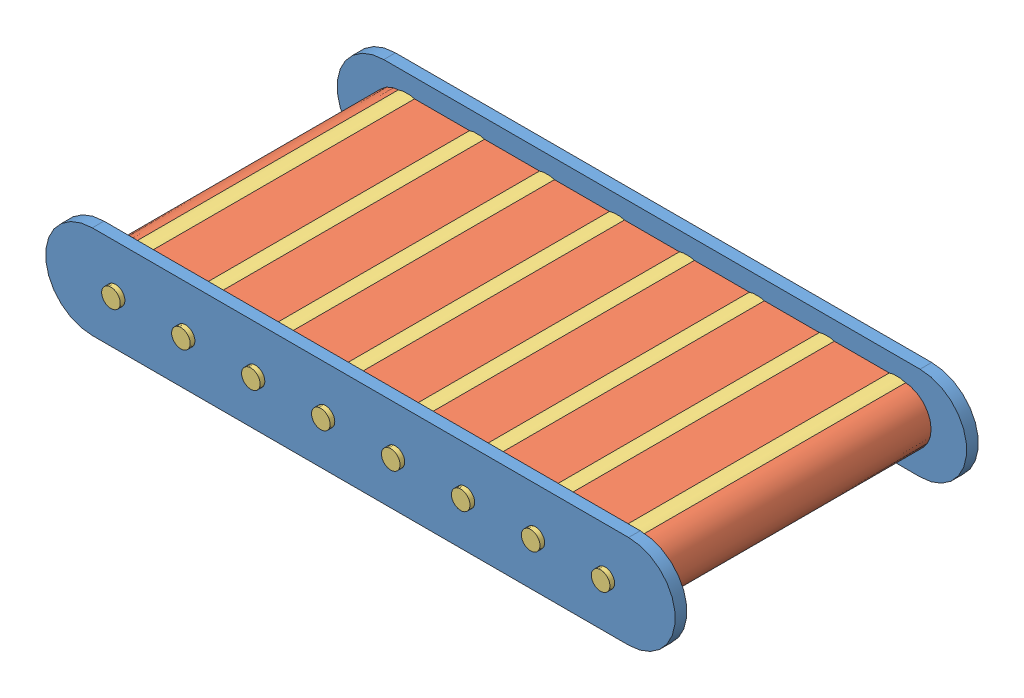
SolidWorks assembly Assem1, configuration Défaut. Lengths in mm.
Overall size (270 40 134).
10 component instances, 3 part files, 4 mates.
Components (placement in the parent):
- ajneb-1: ajneb [Défaut] at (-102.1225 -28.6307 270) size (270 40 130)
- bande-1: bande [Défaut] at (-102.1225 -28.6307 270) size (239.5 24 120)
- rouleau-1: rouleau [Défaut] at (-102.1225 -28.6307 270) x (0.763755 0.645506 0) z (0.645506 -0.763755 0) size (25 134 25)
- rouleau-2: rouleau [Défaut] at (-72.1225 -28.6307 270) x (0.763755 0.645506 0) z (0.645506 -0.763755 0) size (25 134 25)
- rouleau-3: rouleau [Défaut] at (-42.1225 -28.6307 270) x (0.763755 0.645506 0) z (0.645506 -0.763755 0) size (25 134 25)
- rouleau-4: rouleau [Défaut] at (-12.1225 -28.6307 270) x (0.763755 0.645506 0) z (0.645506 -0.763755 0) size (25 134 25)
- rouleau-5: rouleau [Défaut] at (17.8775 -28.6307 270) x (0.763755 0.645506 0) z (0.645506 -0.763755 0) size (25 134 25)
- rouleau-6: rouleau [Défaut] at (47.8775 -28.6307 270) x (0.763755 0.645506 0) z (0.645506 -0.763755 0) size (25 134 25)
- rouleau-7: rouleau [Défaut] at (77.8775 -28.6307 270) x (0.763755 0.645506 0) z (0.645506 -0.763755 0) size (25 134 25)
- rouleau-8: rouleau [Défaut] at (107.8775 -28.6307 270) x (0.763755 0.645506 0) z (0.645506 -0.763755 0) size (25 134 25)
Mates (geometry in assembly coordinates):
- Coincident1: coincident aligned: plane of ajneb-1 through (-102.1225 -28.6307 270) normal (0 0 1); plane of rouleau-1
- Concentric1: concentric aligned: circle of ajneb-1; circle of rouleau-1
- Coincident3: coincident aligned: circle of ajneb-1; circle of bande-1
- Coincident4: coincident aligned: circle of ajneb-1; circle of bande-1
